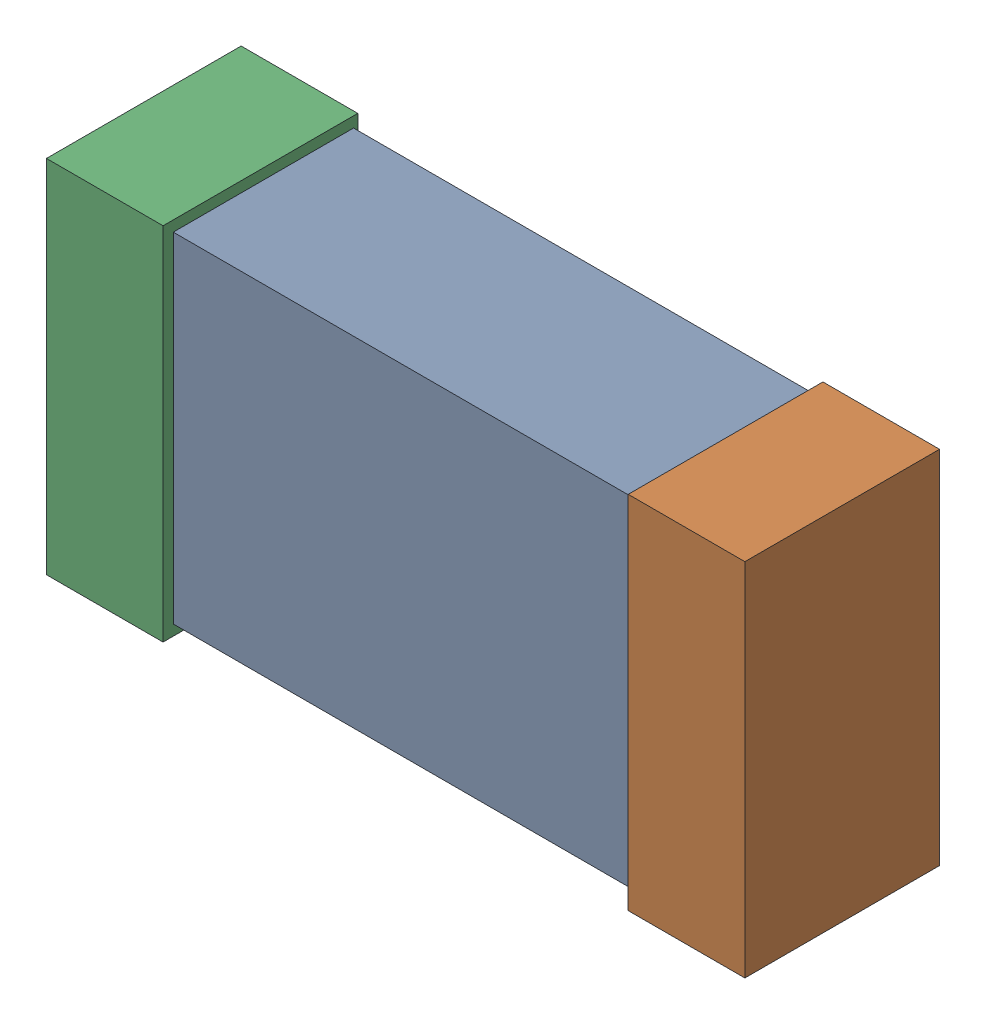
SolidWorks assembly C18, configuration Default. Lengths in mm.
Overall size (1.65 0.85 0.46).
6 component instances, 2 part files, 0 mates.
Components (placement in the parent):
- 432120720_11-1: 432120720_11 [Default] at (48.0999 15.5103 -0.8615) size (1.5 0.8 0.42)
  - Extruded (12)-1: Extruded (12) [Default] at origin size (1.5 0.8 0.42)
- 432120464_22-1: 432120464_22 [Default] at (48.7857 15.5103 -0.8715) size (0.28 0.85 0.46)
  - Extruded (11)-1: Extruded (11) [Default] at origin size (0.28 0.85 0.46)
- 432120464_23-1: 432120464_23 [Default] at (47.4142 15.5103 -0.8715) size (0.28 0.85 0.46)
  - Extruded (11)-1: Extruded (11) [Default] at origin size (0.28 0.85 0.46)
